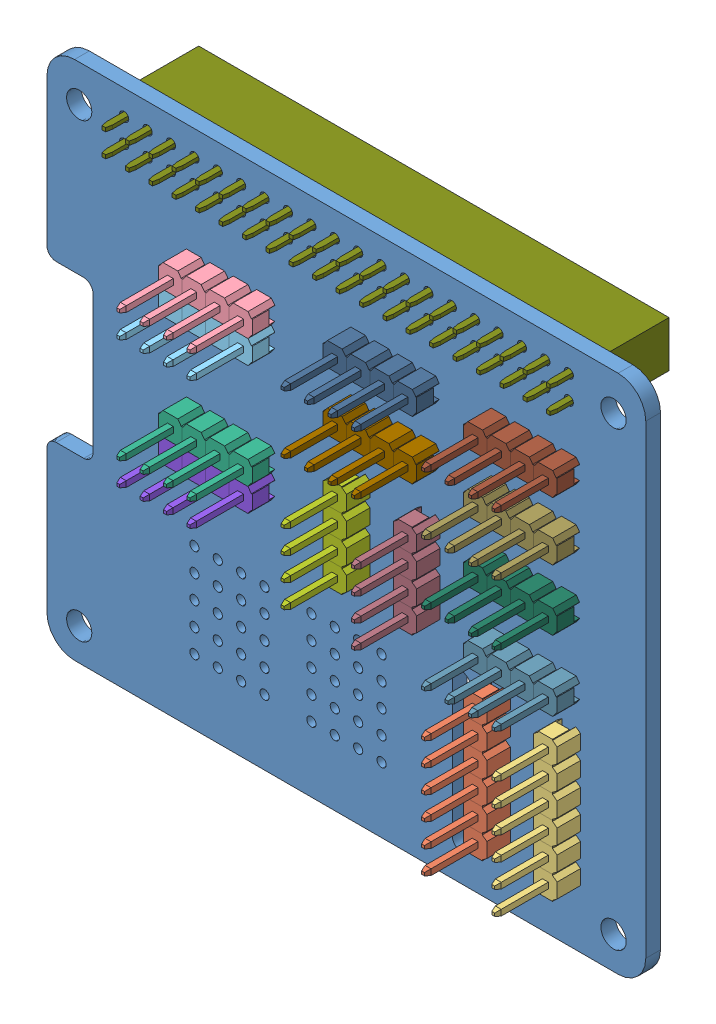
SolidWorks assembly ruben, configuration Predeterminado. Lengths in mm.
Overall size (209.83 107 17.7).
16 component instances, 16 part files, 3 mates.
Components (placement in the parent):
- Pcb-1: Pcb [Predeterminado] at (-123.559 94.036 0) size (209.83 107 1.6)
- Pin_Header_Straight_1x06_-1: Pin_Header_Straight_1x06_ [Predeterminado] at (16.522 -14.803 0) x (0 -1 0) z (0 0 1) size (15.24 2.54 11.2)
- Pin_Header_Straight_1x06_001-1: Pin_Header_Straight_1x06_001 [Predeterminado] at (24.142 -14.803 0) x (0 -1 0) z (0 0 1) size (15.24 2.54 11.2)
- Pin_Header_Straight_1x04_-1: Pin_Header_Straight_1x04_ [Predeterminado] at (-12.7515 15.2325 0) x (-1 0 0) z (0 0 1) size (10.16 2.54 11.2)
- Pin_Header_Straight_1x04_001-1: Pin_Header_Straight_1x04_001 [Predeterminado] at (-12.7515 12.6925 0) x (-1 0 0) z (0 0 1) size (10.16 2.54 11.2)
- Pin_Header_Straight_1x04_002-1: Pin_Header_Straight_1x04_002 [Predeterminado] at (-12.7515 1.326 0) x (-1 0 0) z (0 0 1) size (10.16 2.54 11.2)
- Pin_Header_Straight_1x04_004-1: Pin_Header_Straight_1x04_004 [Predeterminado] at (1.282 0.056 0) x (0 -1 0) z (0 0 1) size (10.16 2.54 11.2)
- Pin_Header_Straight_1x04_003-1: Pin_Header_Straight_1x04_003 [Predeterminado] at (-12.7515 -1.214 0) x (-1 0 0) z (0 0 1) size (10.16 2.54 11.2)
- Pin_Header_Straight_1x04_006-1: Pin_Header_Straight_1x04_006 [Predeterminado] at (5.092 10.47 0) x (-1 0 0) z (0 0 1) size (10.16 2.54 11.2)
- Pin_Header_Straight_1x04_005-1: Pin_Header_Straight_1x04_005 [Predeterminado] at (5.092 16.82 0) x (-1 0 0) z (0 0 1) size (10.16 2.54 11.2)
- Pin_Header_Straight_1x04_007-1: Pin_Header_Straight_1x04_007 [Predeterminado] at (20.332 16.82 0) x (-1 0 0) z (0 0 1) size (10.16 2.54 11.2)
- Pin_Header_Straight_1x04_008-1: Pin_Header_Straight_1x04_008 [Predeterminado] at (20.332 10.47 0) x (-1 0 0) z (0 0 1) size (10.16 2.54 11.2)
- Pin_Header_Straight_1x04_009-1: Pin_Header_Straight_1x04_009 [Predeterminado] at (8.902 0.056 0) x (0 -1 0) z (0 0 1) size (10.16 2.54 11.2)
- Pin_Header_Straight_1x04_010-1: Pin_Header_Straight_1x04_010 [Predeterminado] at (20.332 -3.754 0) x (-1 0 0) z (0 0 1) size (10.16 2.54 11.2)
- Pin_Header_Straight_1x04_011-1: Pin_Header_Straight_1x04_011 [Predeterminado] at (20.332 3.866 0) x (-1 0 0) z (0 0 1) size (10.16 2.54 11.2)
- female_header_a-bl254-dg-g40d-1: female_header_a-bl254-dg-g40d [Default] at (0 24.25 -1) x (1 0 0) z (0 1 0) size (51.05 11.7 5)
Mates (geometry in assembly coordinates):
- Coincidente1: coincident anti-aligned: plane of Pcb-1 through (-31.5 -8.75 -1.6) normal (0 0 -1); plane of female_header_a-bl254-dg-g40d-1 through (25.525 22.475 -1.6) normal (0 0 1)
- Distancia1: distance = 1.5 mm: line of Pcb-1 through (-29.5 28.25 -1.6) axis (1 0 0); plane of female_header_a-bl254-dg-g40d-1 through (25.525 26.75 -1) normal (0 1 0)
- Distancia2: distance = 8.05 mm: plane of female_header_a-bl254-dg-g40d-1 through (-24.45 22.78 1.55) normal (-1 0 0); line of Pcb-1 through (-32.5 9.25 0) axis (0 1 0)
